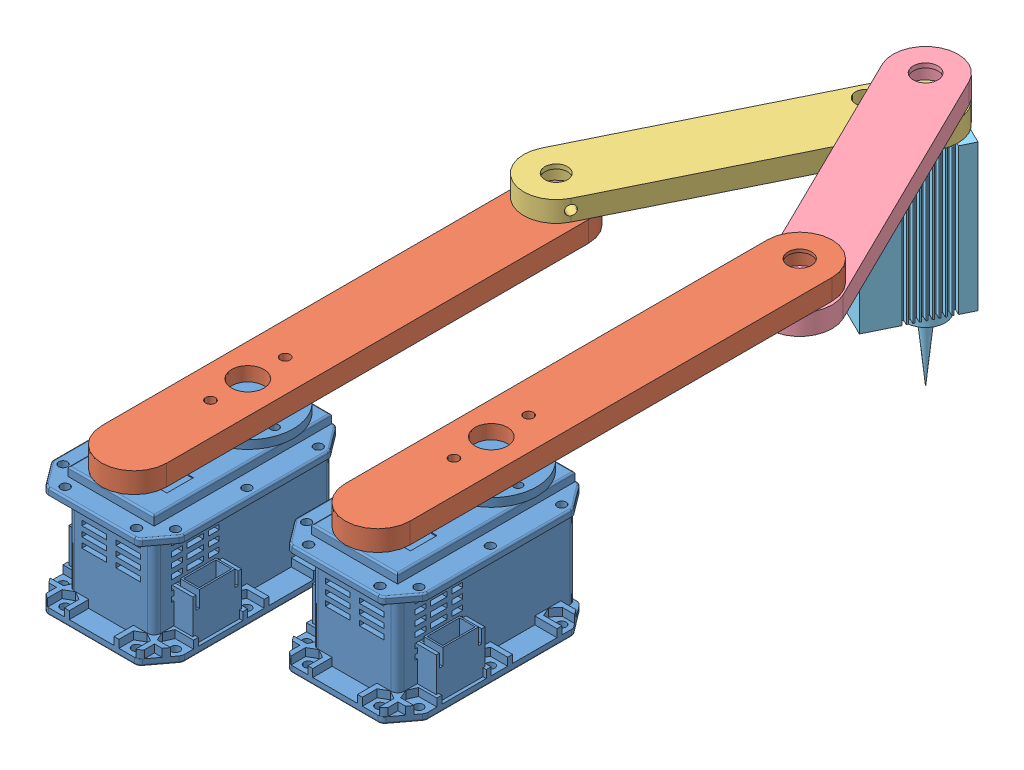
SolidWorks assembly manipulador, configuration Predeterminado. Lengths in mm.
Overall size (115.2 91.05 232.77).
7 component instances, 5 part files, 21 mates.
Components (placement in the parent):
- Servomotor MX 64T-1: Servomotor MX 64T [Default] x (-1 0 0) z (0 -1 0) size (40.2 62.1 45.8)
- Servomotor MX 64T-2: Servomotor MX 64T [Default] at (75 22.05 0) x (-1 0 0) z (0 -1 0) size (40.2 62.1 45.8)
- manivela-1: manivela [Predeterminado] at (-0.0006 43.65 -47.55) x (-1 0 0) z (0 -1 0) size (20 150 6.35)
- manivela-2: manivela [Predeterminado] at (74.9994 65.7 -47.55) x (-1 0 0) z (0 -1 0) size (20 150 6.35)
- manivela L-1: manivela L [Predeterminado] at (18.7494 44.65 -150.6904) x (0.89742 0 0.441176) z (0 1 0) size (20 105 6.35)
- manivela LL-2: manivela LL [Predeterminado] at (56.2494 58.35 -150.6904) x (-0.89742 0 0.441176) z (0 -1 0) size (20 105 6.35)
- laser-1: laser [Predeterminado] at (35.2935 44.65 -184.3436) x (-0.89742 0 -0.441176) z (0 -1 0) size (20 27.3 70)
Mates (geometry in assembly coordinates):
- Coincidente3: coincident anti-aligned: plane of Servomotor MX 64T-1 through (0 0 0) normal (0 -1 0); plane of assembly through (0 0 0) normal (0 1 0)
- Coincidente4: coincident anti-aligned: plane of Servomotor MX 64T-1 through (0 0 0) normal (-1 0 0); plane of assembly through (0 0 0) normal (1 0 0)
- Coincidente5: coincident anti-aligned: plane of Servomotor MX 64T-1 through (0 0 0) normal (0 0 -1); plane of assembly through (0 0 0) normal (0 0 1)
- Coincidente12: coincident aligned: plane of Servomotor MX 64T-1 through (-13.25 30 24.55) normal (0 0 1); plane of Servomotor MX 64T-2 through (61.75 52.05 24.55) normal (0 0 1)
- Paralelo2: parallel aligned: plane of Servomotor MX 64T-1 through (0 -5.5 0) normal (0 -1 0); plane of Servomotor MX 64T-2 through (75 16.55 0) normal (0 -1 0)
- Concéntrica1: concentric aligned: cylinder of Servomotor MX 64T-1 through (-0.0006 39.3 -17.55) axis (0 -1 0) radius 5; cylinder of manivela-1 through (-0.0006 43.65 -17.55) axis (0 -1 0) radius 5
- Coincidente14: coincident anti-aligned: plane of Servomotor MX 64T-1 through (-0.0006 37.3 -17.55) normal (0 1 0); plane of manivela-1 through (-0.0006 37.3 -112.55) normal (0 -1 0)
- Coincidente35: coincident aligned: line of manivela-1 through (-0.0006 42.7 -112.55) axis (0 -1 0); line of manivela L-1 through (-0.0006 49.65 -112.55) axis (0 -1 0)
- Distancia2: distance = 1 mm anti-aligned: plane of manivela-1 through (-0.0006 43.65 -112.55) normal (0 1 0); plane of manivela L-1 through (37.4994 44.65 -188.8307) normal (0 -1 0)
- Coincidente40: coincident aligned: line of Servomotor MX 64T-2 through (74.9994 77.9894 -17.55) axis (0 -1 0); axis of manivela-2 through (74.9994 65.7 -17.55) axis (0 -1 0)
- Coincidente41: coincident anti-aligned: line of manivela-2 through (74.9994 64.75 -112.55) axis (0 -1 0); line of manivela LL-2 through (74.9994 53.35 -112.55) axis (0 1 0)
- Distancia5: distance = 1 mm anti-aligned: plane of manivela LL-2 through (37.4994 58.35 -188.8307) normal (0 1 0); plane of manivela-2 through (74.9994 59.35 -112.55) normal (0 -1 0)
- Coincidente43: coincident anti-aligned: line of manivela L-1 through (37.4994 46 -188.8307) axis (0 1 0); line of manivela LL-2 through (37.4994 57 -188.8307) axis (0 -1 0)
- Distancia6: distance = 1 mm anti-aligned: plane of manivela L-1 through (37.4994 51 -188.8307) normal (0 1 0); plane of manivela LL-2 through (37.4994 52 -188.8307) normal (0 -1 0)
- Coincidente45: coincident anti-aligned: plane of Servomotor MX 64T-2 through (74.9994 59.35 -17.55) normal (0 1 0); plane of manivela-2 through (74.9994 59.35 -112.55) normal (0 -1 0)
- Coincidente46: coincident aligned: line of manivela LL-2 through (37.4994 57 -188.8307) axis (0 -1 0); line of laser-1 through (37.4994 44.65 -188.8307) axis (0 -1 0)
- Coincidente47: coincident aligned: plane of manivela L-1 through (46.4736 51 -184.419) normal (0.89742 0 0.441176); plane of laser-1 through (50.2898 -0.35 -192.1817) normal (0.89742 0 0.441176)
- Coincidente48: coincident anti-aligned: plane of manivela L-1 through (37.4994 44.65 -188.8307) normal (0 -1 0); plane of laser-1 through (35.2935 44.65 -184.3436) normal (0 1 0)
- Distancia7: distance = 75 mm aligned: plane of Servomotor MX 64T-1 through (0 0 0) normal (-1 0 0); plane of Servomotor MX 64T-2 through (75 22.05 0) normal (-1 0 0)
- Paralelo4: parallel aligned: plane of Servomotor MX 64T-2 through (88.25 52.05 -30.55) normal (1 0 0); plane of manivela-2 through (84.9994 59.35 -112.55) normal (1 0 0)
- Paralelo5: parallel aligned: plane of Servomotor MX 64T-1 through (-13.25 30 -30.55) normal (-1 0 0); plane of manivela-1 through (-10.0006 37.3 -112.55) normal (-1 0 0)
